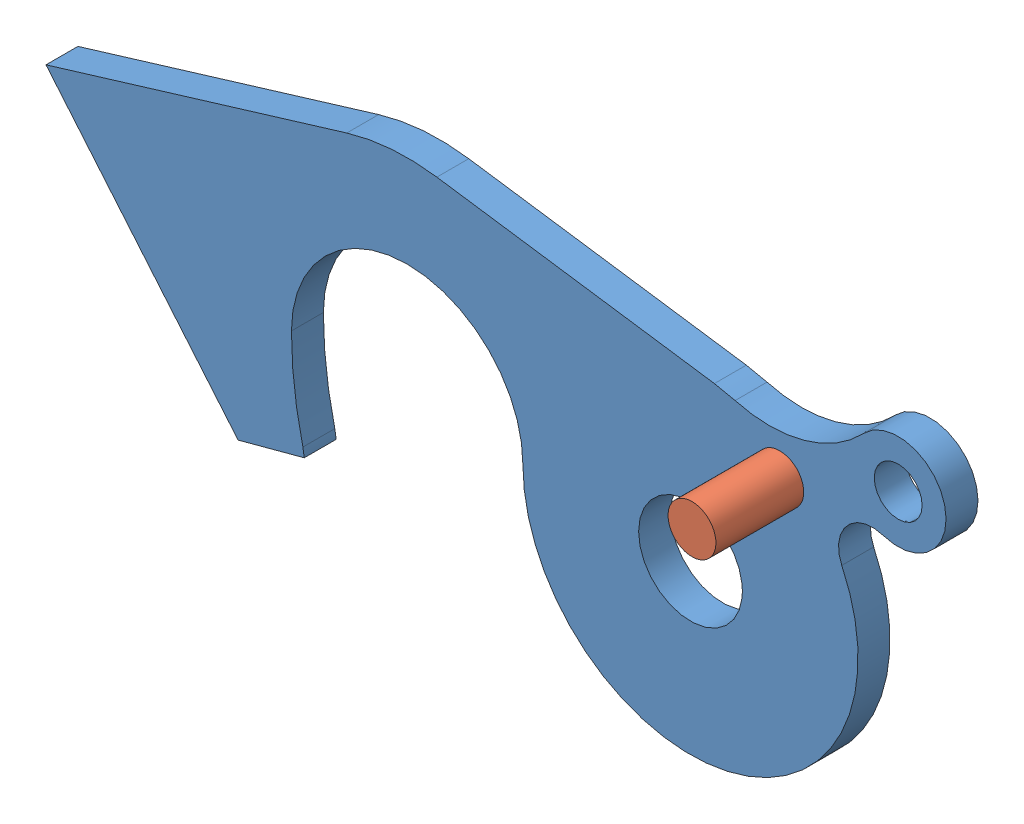
SolidWorks assembly ТП.016.10.03.00 - Собачка с фиксатором, configuration Левая. Lengths in mm.
Overall size (112.78 47.58 15).
2 component instances, 2 part files, 3 mates.
Components (placement in the parent):
- ТП.016.10.03.01 - Собачка навески (Ст3 S-4мм)-1: ТП.016.10.03.01 - Собачка навески (Ст3 S-4мм) [Левая] at origin size (112.78 47.58 4)
- ТП.016.10.03.02 - Фиксатор-курок-1: ТП.016.10.03.02 - Фиксатор-курок [--] at (11.1898 14.5852 15) x (0.982471 0.186418 0) z (-0.186418 0.982471 0) size (6 15 6)
Mates (geometry in assembly coordinates):
- Концентричный1: concentric: cylinder of ТП.016.10.03.01 - Собачка навески (Ст3 S-4мм)-1 through (11.1898 14.5852 4) axis (0 0 -1) radius 3; cylinder of ТП.016.10.03.02 - Фиксатор-курок-1 through (11.1898 14.5852 0) axis (0 0 1) radius 3
- Совпадение1: coincident: plane of ТП.016.10.03.01 - Собачка навески (Ст3 S-4мм)-1 through (-35.5 0 4) normal (0 0 1); plane of ТП.016.10.03.02 - Фиксатор-курок-1 through (11.0048 13.9906 4) normal (0 0 1)
- Совпадение2: coincident: plane of ТП.016.10.03.01 - Собачка навески (Ст3 S-4мм)-1 through (-35.5 0 0) normal (0 0 -1); plane of ТП.016.10.03.02 - Фиксатор-курок-1 through (11.1898 14.5852 0) normal (0 0 -1)
